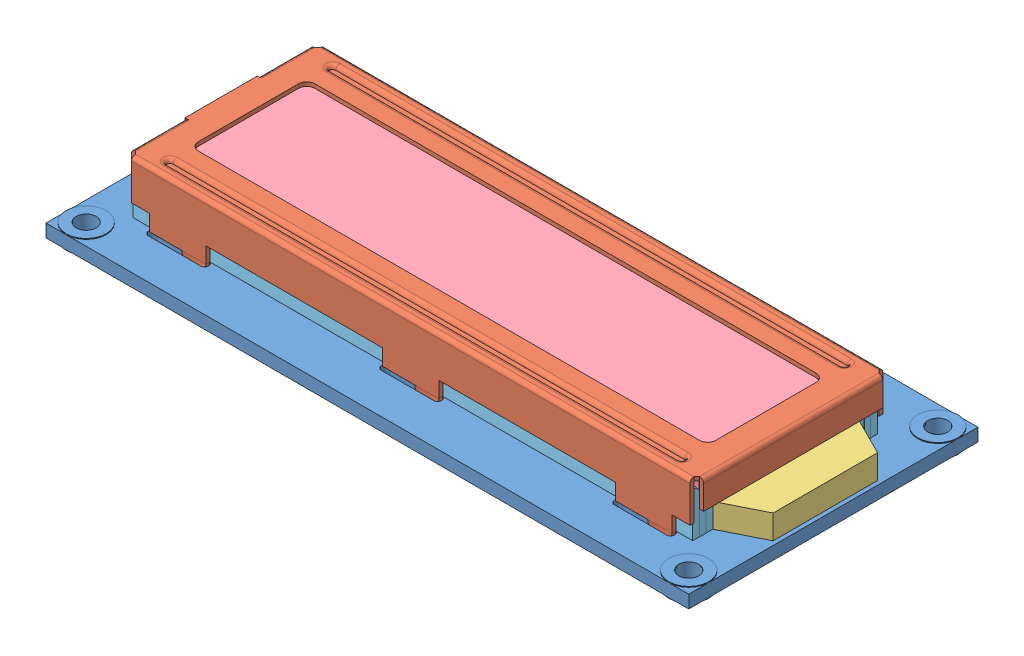
SolidWorks assembly LCD, configuration Default. Lengths in mm.
Overall size (80 23.01 36).
9 component instances, 7 part files, 0 mates.
Components (placement in the parent):
- LCD_PCB-1: LCD_PCB [Default] at (-1.4055 -3.4444 3.0818) size (80 1.8 36)
- metal_casing-1: metal_casing [Default] at (-1.5055 3.0556 3.5818) size (71.2 10.63 25.26)
- LCDbacklight-1: LCDbacklight [Default] at (-1.7555 -3.4444 3.5818) size (74.7 3 18)
- LCD-1: LCD [Default] at (-1.6055 1.9556 3.5818) size (70.3 2.1 22)
- conductors-1: conductors [Default] at (-1.7555 -0.6944 13.8318) size (69.7 5.5 2.5)
- conductors-2: conductors [Default] at (-1.7555 -0.6944 -6.6682) size (69.7 5.5 2.5)
- 1x8 Male Pin Header-1: 1x8 Male Pin Header [Default] at (4.6945 -5.0444 -12.4182) x (-1 0 0) z (0 0 1) size (20.32 13.54 2.5)
- 1x8 Male Pin Header-2: 1x8 Male Pin Header [Default] at (-33.4055 -5.0444 -12.4182) x (1 0 0) z (0 0 -1) size (20.32 13.54 2.5)
- Header Female 1x16.step-1: Header Female 1x16.step [Default] at (-14.3555 -11.8719 -12.4182) size (40.79 11.87 2.48)
